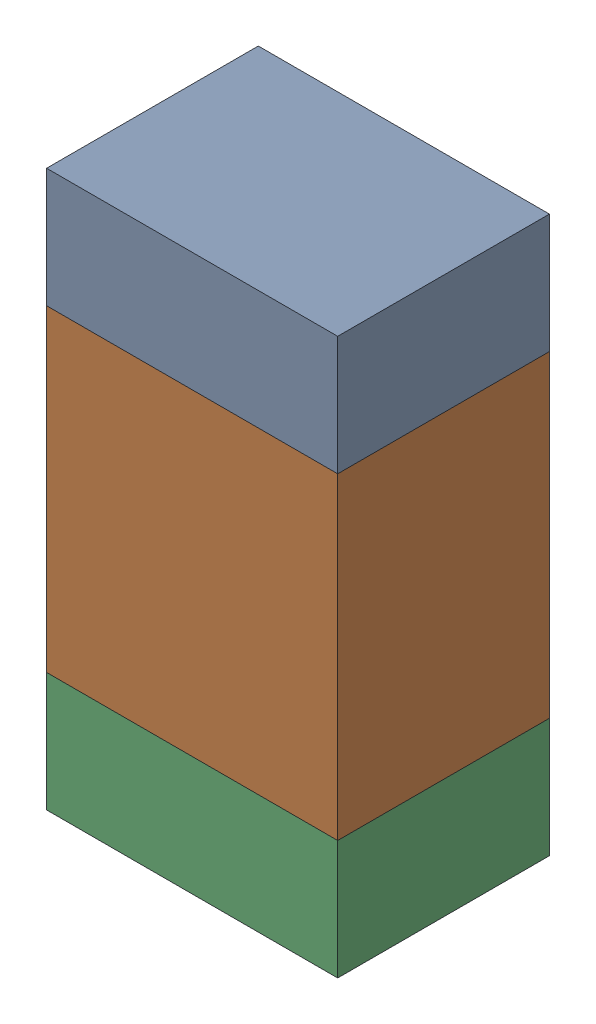
SolidWorks assembly R110_1PCB, configuration Default. Lengths in mm.
Overall size (0.55 1.05 0.4).
6 component instances, 2 part files, 0 mates.
Components (placement in the parent):
- 846483288-1: 846483288 [Default] at (115.7001 115.6124 0) size (0.55 0.22 0.4)
  - Extruded_12-1: Extruded_12 [Default] at origin size (0.55 0.22 0.4)
- 846483424-1: 846483424 [Default] at (115.7001 115.1999 0) size (0.55 0.6 0.4)
  - Extruded_13-1: Extruded_13 [Default] at origin size (0.55 0.6 0.4)
- 846483288-2: 846483288 [Default] at (115.7001 114.7874 0) size (0.55 0.22 0.4)
  - Extruded_12-1: Extruded_12 [Default] at origin size (0.55 0.22 0.4)
